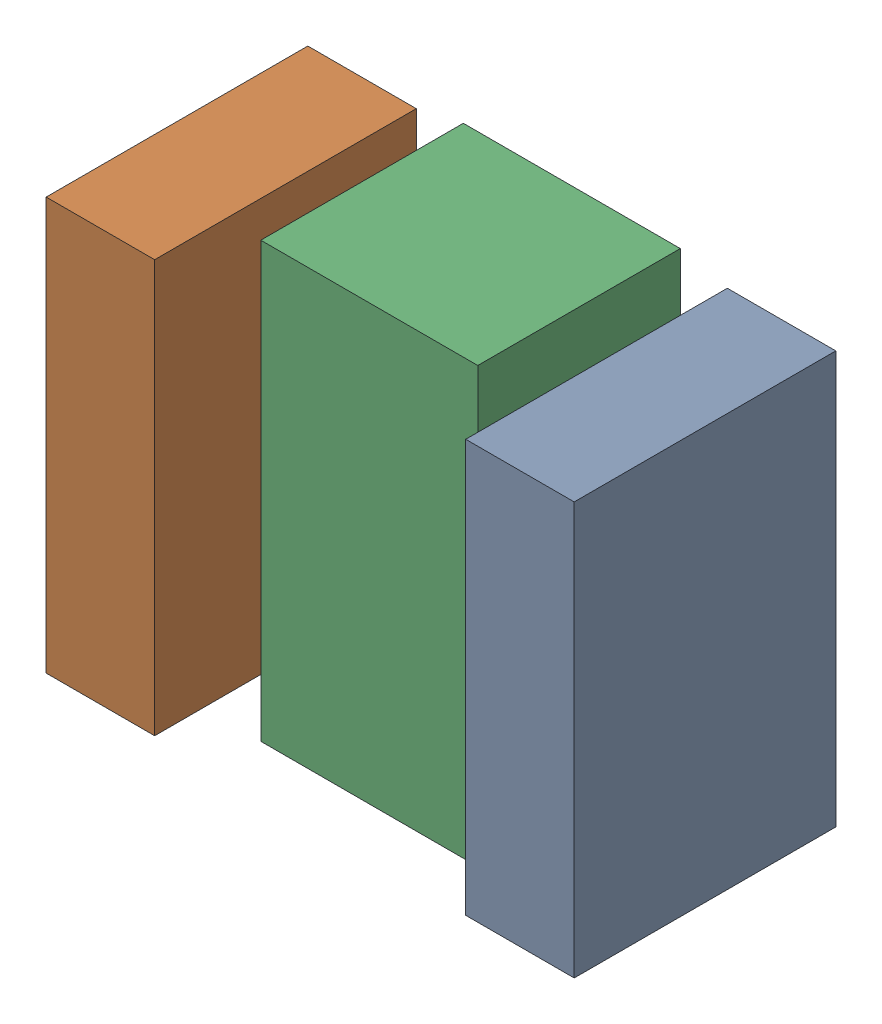
SolidWorks assembly C11_Motor_11Kanaloa_v2.0.0_Motor, configuration Default. Lengths in mm.
Overall size (3.65 3 1.81).
6 component instances, 2 part files, 0 mates.
Components (placement in the parent):
- 334788400-1: 334788400 [Default] at (121.608 163.83 0) size (0.75 2.85 1.81)
  - Extruded_5-1: Extruded_5 [Default] at origin size (0.75 2.85 1.81)
- 334788400-2: 334788400 [Default] at (118.708 163.83 0) size (0.75 2.85 1.81)
  - Extruded_5-1: Extruded_5 [Default] at origin size (0.75 2.85 1.81)
- 334788656-1: 334788656 [Default] at (120.158 163.83 0) size (1.5 3 1.4)
  - Extruded_1-1: Extruded_1 [Default] at origin size (1.5 3 1.4)
